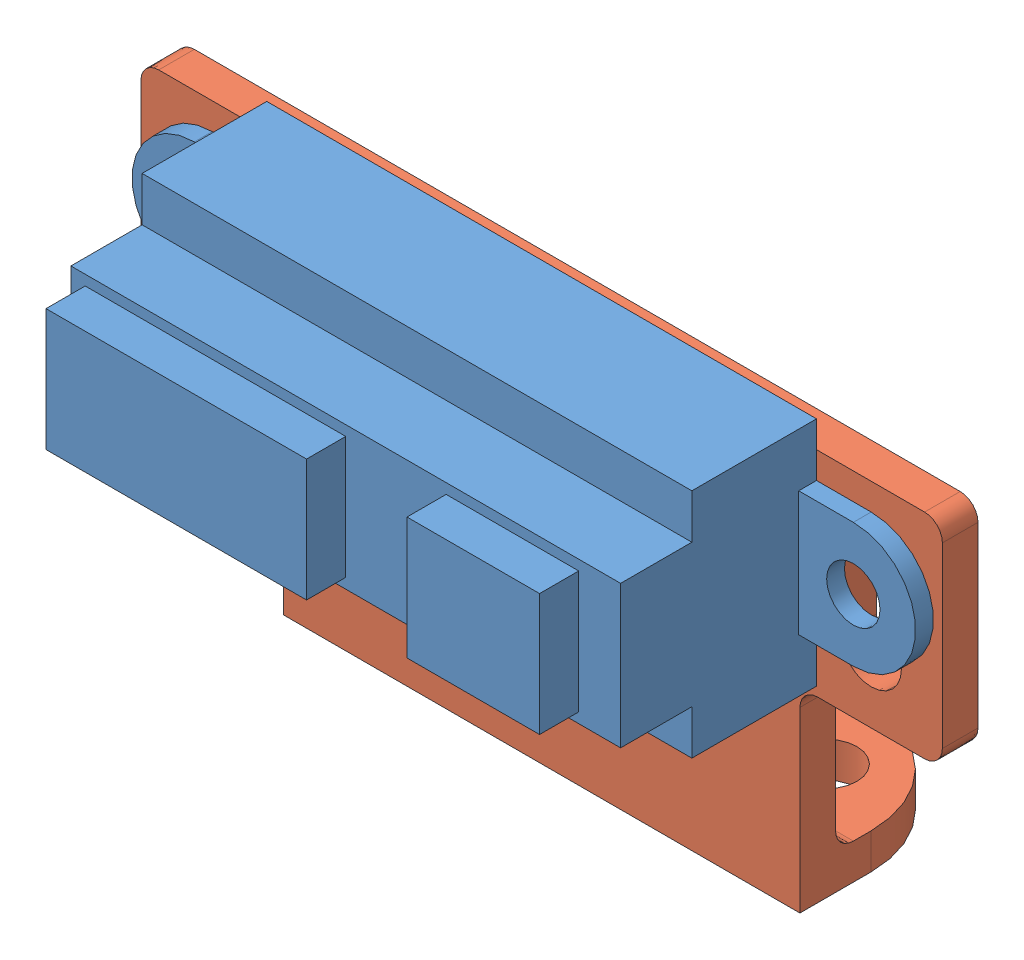
SolidWorks assembly 红外固定部分, configuration 默认. Lengths in mm.
Overall size (45 24.5 23.2).
2 component instances, 2 part files, 3 mates.
Components (placement in the parent):
- 红外传感器-1: 红外传感器 [默认] at origin size (44 13 13.2)
- 011红外传感器支架-1: 011红外传感器支架 [默认] x (-1 0 0) z (0 0 -1) size (45 23 10)
Mates (geometry in assembly coordinates):
- 重合1: coincident aligned: plane of 红外传感器-1 through (0 0 0) normal (0 0 -1); plane of 011红外传感器支架-1 through (0 0 0) normal (0 0 -1)
- 重合2: coincident anti-aligned: plane of 011红外传感器支架-1 through (0 0 0) normal (-1 0 0)
- 重合3: coincident aligned: plane of 011红外传感器支架-1 through (0 0 0) normal (0 1 0)
